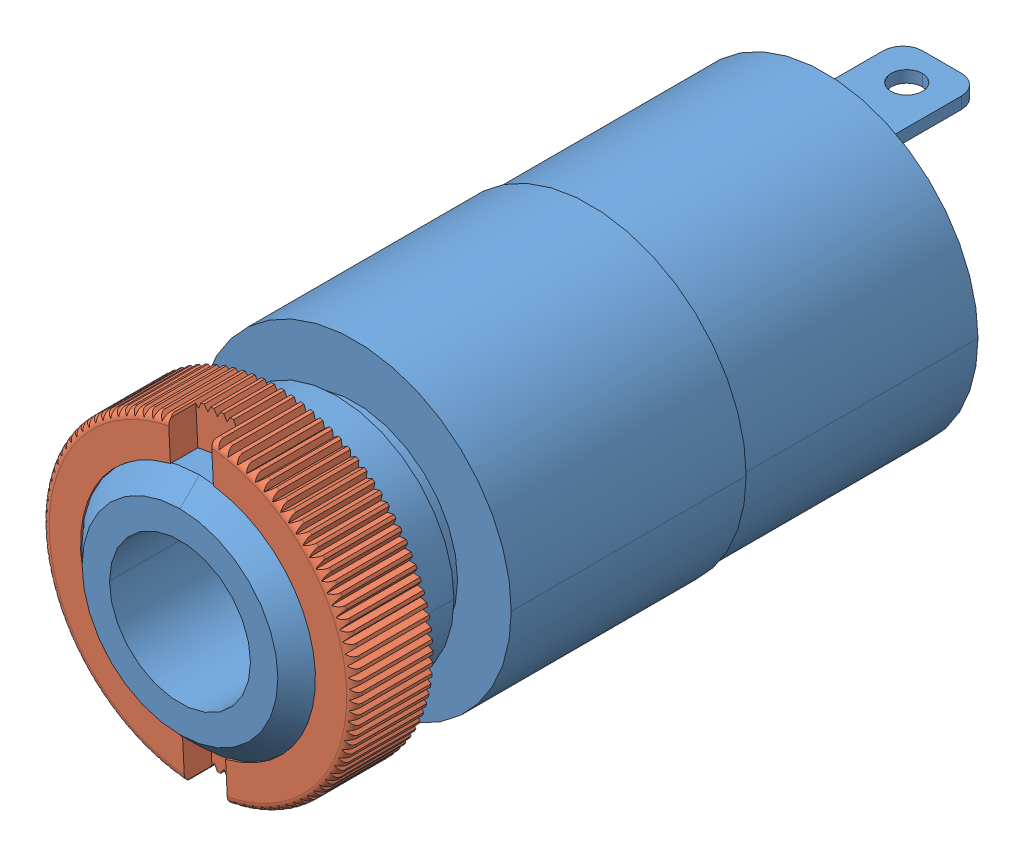
SolidWorks assembly 3_5MM Panel Mount Audio Jack - 3 Connector, configuration Standard. Lengths in mm.
Overall size (8.44 8.41 20.46).
2 component instances, 2 part files, 6 mates.
Components (placement in the parent):
- 3.5MM Panel Mount Audio Jack - 4 Connector - korpus-1: 3.5MM Panel Mount Audio Jack - 4 Connector - korpus [Standard] at (-4 -4 -4) size (8 8 20.46)
- 3.5MM Panel Mount Audio Jack - 4 Connector - nakr_X2_0119_X0_tka-1: 3.5MM Panel Mount Audio Jack - 4 Connector - nakr_X2_0119_X0_tka [Standard] at (-4 -4 -2.46) x (0.998616 0.052592 0) z (0 0 1) size (8.03 8 2.01)
Mates (geometry in assembly coordinates):
- Konzentrisch1: concentric: cylinder of 3.5MM Panel Mount Audio Jack - 4 Connector - korpus-1 through (-4 -4 -4) axis (0 0 1) radius 3; cylinder of 3.5MM Panel Mount Audio Jack - 4 Connector - nakr_X2_0119_X0_tka-1 through (-4 -4 -2.6976) axis (0 0 1) radius 3
- Deckungsgleich1: coincident aligned: plane of 3.5MM Panel Mount Audio Jack - 4 Connector - korpus-1 through (-4 -4 0) normal (0 0 1); plane of assembly through (0 0 0) normal (0 0 1)
- Tangential1: tangent aligned: cylinder of 3.5MM Panel Mount Audio Jack - 4 Connector - korpus-1 through (-4 -4 -4.46) axis (0 0 -1) radius 4; plane of assembly through (0 0 0) normal (0 1 0)
- Tangential2: tangent aligned: cylinder of 3.5MM Panel Mount Audio Jack - 4 Connector - korpus-1 through (-4 -4 -4.46) axis (0 0 -1) radius 4; plane of assembly through (0 0 0) normal (1 0 0)
- Parallel1: parallel aligned: plane of 3.5MM Panel Mount Audio Jack - 4 Connector - korpus-1 through (-5 -1.35 -16.46) normal (0 1 0); plane of assembly through (0 0 0) normal (0 1 0)
- LimitAbstand1: limit distance = 2 mm anti-aligned: plane of 3.5MM Panel Mount Audio Jack - 4 Connector - nakr_X2_0119_X0_tka-1 through (-4 -4 -2.46) normal (0 0 -1); plane of 3.5MM Panel Mount Audio Jack - 4 Connector - korpus-1 through (-4 -4 -4.46) normal (0 0 1)
